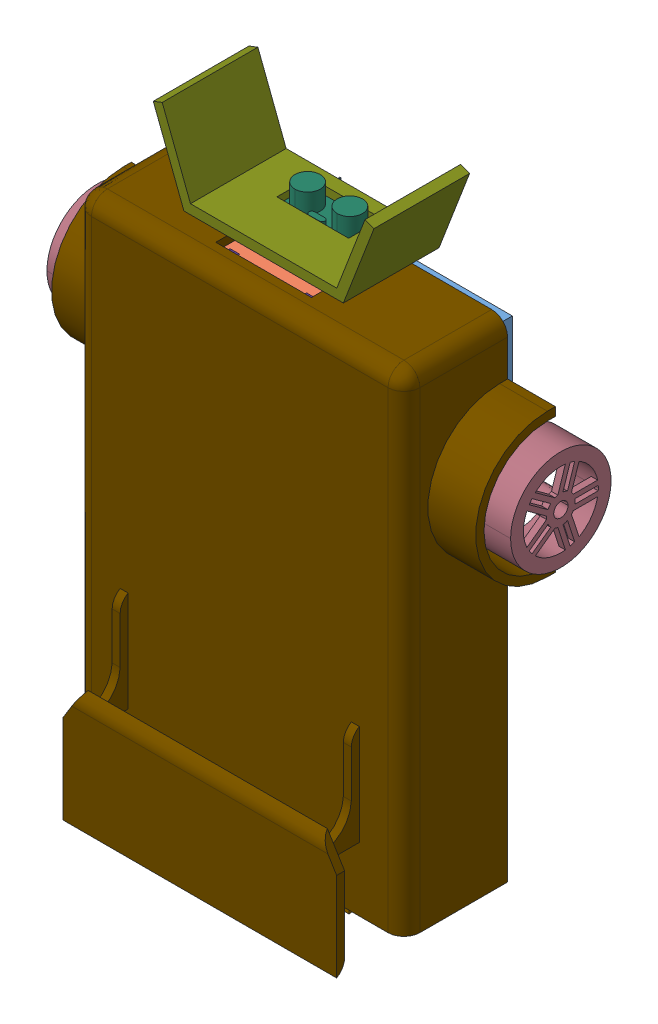
SolidWorks assembly design_functional_final, configuration 기본. Lengths in mm.
Overall size (290.8 392.49 151.94).
23 component instances, 18 part files, 60 mates.
Components (placement in the parent):
- bottom-1: bottom [기본] at (17.9171 -162.0104 297) size (200 300 6)
- frontWall-1: frontWall [기본] at (17.9171 129.9896 303) size (196 6 151.94)
- sideWall x2-1: sideWall x2 [기본] at (109.9171 83.9896 303) x (0 -1 0) z (0 0 1) size (92 6 56)
- sideWall x2-2: sideWall x2 [기본] at (-80.0829 83.9896 303) x (0 -1 0) z (0 0 1) size (92 6 56)
- midWall-1: midWall [기본] at (17.9171 43.9896 303) x (1 0 0) z (0 -1 0) size (184 56 6)
- midWall_2 x2-1: midWall_2 x2 [기본] at (61.6659 -58.0104 303) x (0 -1 0) z (0 0 1) size (192 6 31)
- midWall_2 x2-2: midWall_2 x2 [기본] at (-25.8316 -58.0104 303) x (0 1 0) z (0 0 1) size (192 6 31)
- backWall-1: backWall [기본] at (17.9171 -160.0104 303) size (100 6 31)
- motor.step-1: motor.step [기본] at (-22.6829 62.5396 323.0909) x (0 -0.999178 -0.040541) z (0 0.040541 -0.999178) size (37.1 151.83 37.1)
- motor.step-2: motor.step [기본] at (58.5171 62.5396 323.0909) x (0 0.999178 0.040541) z (0 0.040541 -0.999178) size (37.1 151.83 37.1)
- breadboard.step-1: breadboard.step [기본] at (1.1684 -44.5104 303) x (1 0 0) z (0 -1 0) size (54 9.6 165)
- lipo-battery.stp-1: lipo-battery.stp [기본] at (36.6659 211.7279 618.3149) x (0 0 1) z (1 0 0) size (45 230.34 25)
- motorcontroler.step-1: motorcontroler.step [기본] at (2.0184 -0.8795 312.6) x (1 0 0) z (0 -1 0) size (55.7 26.71 104.61)
- arduino-UNO.step-1: arduino-UNO.step [기본] at (2.5393 -66.9971 312.6) x (1 0 0) z (0 -1 0) size (57.5 18.3 80.7)
- front-wheel.stp-1: front-wheel.stp [기본] at (453.7222 -382.8089 285) size (16 22 15.01)
- wheel-basic.step-1: wheel-basic.step [기본] at (-127.4829 62.9896 312) x (0 -1 0) z (0 0 1) size (63 46.5 63)
- wheel-basic.step-2: wheel-basic.step [기본] at (163.3171 62.9896 312) x (0 1 0) z (0 0 1) size (63 46.5 63)
- infrared-sensor.step-1: infrared-sensor.step [기본] at (-7.1329 128.4446 292.35) x (-1 0 0) z (0 -1 0) size (14.1 16.75 36)
- ultrasonic-sensor.step-1: ultrasonic-sensor.step [기본] at (17.7671 147.9896 312.0191) x (-1 0 0) z (0 0 -1) size (45.3 18.15 26.45)
- infrared-sensor.step-2: infrared-sensor.step [기본] at (42.9671 128.4446 292.35) x (-1 0 0) z (0 -1 0) size (14.1 16.75 36)
- Grabber-1: Grabber [기본] at (17.9171 147.9896 293) size (138.41 70.15 60)
- topCover-1: topCover [기본] at (17.9171 43.9896 347) size (184 98 6)
- Cover-2: Cover [기본] at (17.9171 -62.0104 363) size (266 321.72 90)
Mates (geometry in assembly coordinates):
- Coincident1: coincident anti-aligned: plane of bottom-1 through (17.9171 -162.0104 303) normal (0 0 1); plane of frontWall-1 through (17.9171 129.9896 303) normal (0 0 -1)
- Coincident2: coincident anti-aligned: plane of bottom-1 through (109.9171 135.9896 303) normal (-1 0 0); plane of frontWall-1 through (109.9171 129.9896 297) normal (1 0 0)
- Coincident3: coincident anti-aligned: plane of bottom-1 through (58.9171 129.9896 303) normal (0 1 0); plane of frontWall-1 through (115.9171 129.9896 353) normal (0 -1 0)
- Coincident4: coincident anti-aligned: plane of bottom-1 through (17.9171 -162.0104 303) normal (0 0 1); plane of sideWall x2-1 through (109.9171 83.9896 303) normal (0 0 -1)
- Coincident5: coincident anti-aligned: plane of bottom-1 through (109.9171 47.9896 303) normal (1 0 0); plane of sideWall x2-1 through (109.9171 129.9896 353) normal (-1 0 0)
- Coincident6: coincident anti-aligned: plane of bottom-1 through (109.9171 119.9896 303) normal (0 -1 0); plane of sideWall x2-1 through (109.9171 119.9896 297) normal (0 1 0)
- Coincident7: coincident anti-aligned: plane of bottom-1 through (17.9171 -162.0104 303) normal (0 0 1); plane of sideWall x2-2 through (-80.0829 83.9896 303) normal (0 0 -1)
- Coincident8: coincident anti-aligned: plane of bottom-1 through (-74.0829 113.9896 303) normal (-1 0 0); plane of sideWall x2-2 through (-74.0829 129.9896 353) normal (1 0 0)
- Coincident9: coincident anti-aligned: plane of bottom-1 through (-74.0829 119.9896 303) normal (0 -1 0); plane of sideWall x2-2 through (-80.0829 119.9896 297) normal (0 1 0)
- Coincident10: coincident anti-aligned: plane of bottom-1 through (17.9171 -162.0104 303) normal (0 0 1); plane of midWall-1 through (109.9171 37.9896 303) normal (0 0 -1)
- Coincident11: coincident anti-aligned: plane of bottom-1 through (-68.0829 43.9896 303) normal (1 0 0); plane of midWall-1 through (-68.0829 37.9896 297) normal (-1 0 0)
- Coincident12: coincident anti-aligned: plane of bottom-1 through (-62.0829 43.9896 303) normal (0 -1 0); plane of midWall-1 through (17.9171 43.9896 303) normal (0 1 0)
- Coincident13: coincident anti-aligned: plane of bottom-1 through (17.9171 -162.0104 303) normal (0 0 1); plane of backWall-1 through (17.9171 -160.0104 303) normal (0 0 -1)
- Coincident14: coincident anti-aligned: plane of bottom-1 through (29.9171 -154.0104 303) normal (0 -1 0); plane of backWall-1 through (-32.0829 -154.0104 328) normal (0 1 0)
- Coincident15: coincident anti-aligned: plane of bottom-1 through (-20.0829 -160.0104 303) normal (-1 0 0); plane of backWall-1 through (-20.0829 -160.0104 297) normal (1 0 0)
- Coincident16: coincident anti-aligned: plane of bottom-1 through (17.9171 -162.0104 303) normal (0 0 1); plane of midWall_2 x2-1 through (61.6659 -58.0104 303) normal (0 0 -1)
- Coincident17: coincident anti-aligned: plane of bottom-1 through (61.6659 31.9896 303) normal (1 0 0); plane of midWall_2 x2-1 through (61.6659 -154.0104 328) normal (-1 0 0)
- Coincident18: coincident anti-aligned: plane of bottom-1 through (61.9171 -148.0104 303) normal (0 1 0); plane of midWall_2 x2-1 through (67.6659 -148.0104 303) normal (0 -1 0)
- Coincident19: coincident anti-aligned: plane of bottom-1 through (-25.8316 31.9896 303) normal (-1 0 0); plane of midWall_2 x2-2 through (-25.8316 37.9896 328) normal (1 0 0)
- Coincident20: coincident anti-aligned: plane of bottom-1 through (-26.0829 -148.0104 303) normal (0 1 0); plane of midWall_2 x2-2 through (-31.8316 -148.0104 303) normal (0 -1 0)
- Coincident21: coincident anti-aligned: plane of bottom-1 through (17.9171 -162.0104 303) normal (0 0 1); plane of midWall_2 x2-2 through (-25.8316 -58.0104 303) normal (0 0 -1)
- Coincident22: coincident: plane of sideWall x2-2 through (-74.0829 129.9896 353) normal (1 0 0); plane of motor.step-1 through (-74.0829 62.5396 323.0909) normal (-1 0 0)
- Concentric1: concentric: cylinder of sideWall x2-2 through (-74.0829 62.9896 312) axis (-1 0 0) radius 6; cylinder of motor.step-1 through (-80.9829 62.9896 312) axis (1 0 0) radius 6
- Tangent1: tangent: plane of midWall-1 through (17.9171 43.9896 303) normal (0 1 0); cylinder of motor.step-1 through (-74.0829 62.5396 323.0909) axis (1 0 0) radius 18.55
- Coincident23: coincident: plane of sideWall x2-1 through (109.9171 129.9896 353) normal (-1 0 0); plane of motor.step-2 through (109.9171 62.5396 323.0909) normal (1 0 0)
- Concentric2: concentric: cylinder of sideWall x2-1 through (115.9171 62.9896 312) axis (-1 0 0) radius 6; cylinder of motor.step-2 through (116.8171 62.9896 312) axis (-1 0 0) radius 6
- Tangent2: tangent: plane of midWall-1 through (17.9171 43.9896 303) normal (0 1 0); cylinder of motor.step-2 through (109.9171 62.5396 323.0909) axis (-1 0 0) radius 18.55
- Coincident24: coincident: plane of midWall_2 x2-2 through (-25.8316 37.9896 328) normal (1 0 0); plane of breadboard.step-1 through (-25.8316 37.9896 312.6) normal (-1 0 0)
- Coincident25: coincident: plane of bottom-1 through (17.9171 -162.0104 303) normal (0 0 1); plane of breadboard.step-1 through (1.1684 -44.5104 303) normal (0 0 -1)
- Coincident26: coincident: plane of midWall-1 through (17.9171 37.9896 303) normal (0 -1 0); plane of breadboard.step-1 through (-25.8316 37.9896 312.6) normal (0 1 0)
- Coincident27: coincident: plane of bottom-1 through (17.9171 -162.0104 303) normal (0 0 1); plane of lipo-battery.stp-1 through (36.6659 -102.0104 303) normal (0 0 -1)
- Coincident30: coincident: plane of midWall_2 x2-1 through (61.6659 -154.0104 328) normal (-1 0 0); plane of lipo-battery.stp-1 through (61.6659 37.9896 303) normal (1 0 0)
- Coincident31: coincident: plane of midWall-1 through (17.9171 37.9896 303) normal (0 -1 0); plane of lipo-battery.stp-1 through (36.6659 37.9896 303) normal (0 1 0)
- Coincident32: coincident anti-aligned: plane of bottom-1 through (17.9171 -162.0104 297) normal (0 0 -1); plane of front-wheel.stp-1 through (6.2997 -127.4584 297) normal (0 0 1)
- Coincident33: coincident: plane of motor.step-1 through (-80.9829 62.9896 312) normal (-1 0 0); plane of wheel-basic.step-1 through (-80.9829 62.9896 312) normal (1 0 0)
- Concentric3: concentric: cylinder of motor.step-1 through (-96.4829 62.9896 312) axis (1 0 0) radius 2.95; cylinder of wheel-basic.step-1 through (-80.9829 62.9896 312) axis (-1 0 0) radius 4.5
- Coincident36: coincident: plane of motor.step-2 through (116.8171 62.9896 312) normal (1 0 0); plane of wheel-basic.step-2 through (116.8171 62.9896 312) normal (-1 0 0)
- Concentric4: concentric: cylinder of motor.step-2 through (132.3171 62.9896 312) axis (-1 0 0) radius 2.95; cylinder of wheel-basic.step-2 through (116.8171 62.9896 312) axis (1 0 0) radius 4.5
- Coincident37: coincident anti-aligned: plane of frontWall-1 through (-4.5829 135.9896 336.5) normal (1 0 0); plane of Grabber-1 through (-4.5829 129.9896 336.5) normal (-1 0 0)
- Coincident38: coincident anti-aligned: plane of frontWall-1 through (-4.5829 135.9896 330.5) normal (0 0 1); plane of Grabber-1 through (-4.5829 129.9896 330.5) normal (0 0 -1)
- Coincident39: coincident aligned: plane of frontWall-1 through (115.9171 129.9896 353) normal (0 -1 0); plane of Grabber-1 through (17.9171 129.9896 293) normal (0 -1 0)
- Coincident44: coincident anti-aligned: plane of ultrasonic-sensor.step-1 through (-4.8829 149.6396 322.1691) normal (0 0 1); plane of Grabber-1 through (-4.5829 153.9896 322.1691) normal (0 0 -1)
- Coincident45: coincident anti-aligned: plane of ultrasonic-sensor.step-1 through (40.4171 149.6396 322.1691) normal (1 0 0); plane of Grabber-1 through (40.4171 153.9896 301.1691) normal (-1 0 0)
- Coincident46: coincident aligned: plane of ultrasonic-sensor.step-1 through (17.7671 147.9896 312.0191) normal (0 -1 0); plane of Grabber-1 through (67.9171 147.9896 353) normal (0 -1 0)
- Coincident47: coincident: plane of breadboard.step-1 through (1.1684 -44.5104 312.6) normal (0 0 1); plane of motorcontroler.step-1 through (2.0184 -0.8795 312.6) normal (0 0 -1)
- Coincident50: coincident anti-aligned: plane of midWall_2 x2-2 through (-25.8316 37.9896 328) normal (1 0 0); plane of motorcontroler.step-1 through (-25.8316 -0.8795 312.6) normal (-1 0 0)
- Coincident51: coincident: plane of breadboard.step-1 through (1.1684 -44.5104 312.6) normal (0 0 1); plane of arduino-UNO.step-1 through (2.5393 -66.9971 312.6) normal (0 0 -1)
- Coincident52: coincident anti-aligned: plane of midWall_2 x2-2 through (-25.8316 37.9896 328) normal (1 0 0); plane of arduino-UNO.step-1 through (-25.8316 -29.1773 319.6) normal (-1 0 0)
- Coincident53: coincident anti-aligned: plane of bottom-1 through (17.9171 -162.0104 297) normal (0 0 -1); plane of infrared-sensor.step-2 through (42.9671 128.4446 297) normal (0 0 1)
- Coincident54: coincident: plane of bottom-1 through (17.9171 -162.0104 297) normal (0 0 -1); plane of infrared-sensor.step-1 through (-7.1329 128.4446 297) normal (0 0 1)
- Coincident55: coincident anti-aligned: plane of bottom-1 through (-82.0829 137.9896 303) normal (0 1 0); plane of infrared-sensor.step-2 through (48.4171 137.9896 282.6) normal (0 -1 0)
- Coincident56: coincident: plane of bottom-1 through (-82.0829 137.9896 303) normal (0 1 0); plane of infrared-sensor.step-1 through (-1.6829 137.9896 282.6) normal (0 -1 0)
- Tangent3: tangent: circle of bottom-1; plane of infrared-sensor.step-2 through (35.9171 113.3446 290.65) normal (-1 0 0)
- Tangent4: tangent: circle of bottom-1; plane of infrared-sensor.step-1 through (-0.0829 144.5446 290.65) normal (1 0 0)
- Coincident59: coincident anti-aligned: plane of frontWall-1 through (-54.0829 129.9896 347) normal (-1 0 0); plane of topCover-1 through (-54.0829 129.9896 353) normal (1 0 0)
- Coincident60: coincident anti-aligned: plane of frontWall-1 through (-60.0829 129.9896 347) normal (0 0 1); plane of topCover-1 through (17.9171 43.9896 347) normal (0 0 -1)
- Coincident61: coincident aligned: plane of frontWall-1 through (-80.0829 135.9896 353) normal (0 1 0); plane of topCover-1 through (-54.0829 135.9896 353) normal (0 1 0)
- Coincident66: coincident anti-aligned: plane of bottom-1 through (17.9171 -162.0104 303) normal (0 0 1); plane of Cover-2 through (17.9171 -62.0104 303) normal (0 0 -1)
- Coincident67: coincident anti-aligned: plane of frontWall-1 through (-80.0829 135.9896 353) normal (0 1 0); plane of Cover-2 through (17.9171 135.9896 303) normal (0 -1 0)
- Coincident68: coincident anti-aligned: plane of sideWall x2-2 through (-80.0829 129.9896 353) normal (-1 0 0); plane of Cover-2 through (-80.0829 -62.0104 303) normal (1 0 0)
